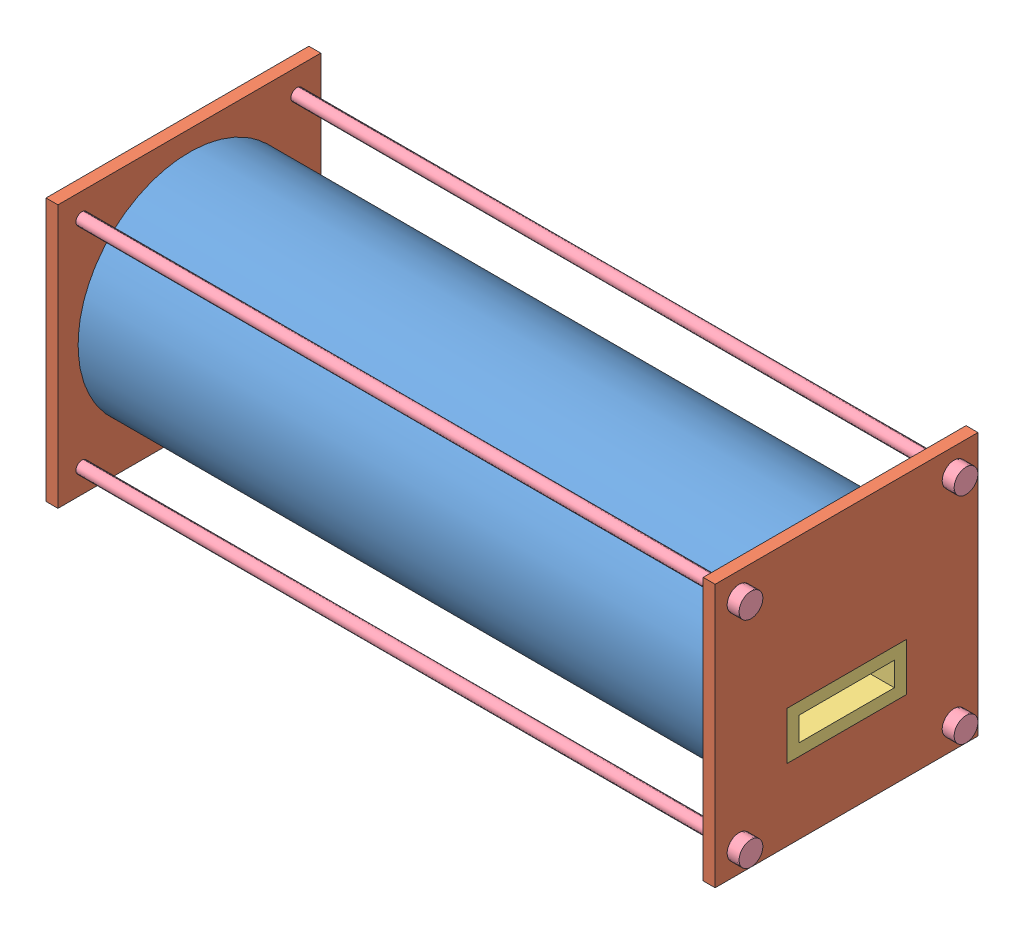
SolidWorks assembly Buoyancy_Cylinder_Assembly_1, configuration Default. Lengths in mm.
Overall size (580 220 220).
8 component instances, 4 part files, 17 mates.
Components (placement in the parent):
- Cylinder Body 1-1: Cylinder Body 1 [Default] at (-321.7289 98.8857 102.5905) size (550 186.35 186.35)
- End Caps 1-1: End Caps 1 [Default] at (233.2711 -11.1143 -7.4095) x (-1 0 0) z (0 0 -1) size (10 220 220)
- End Caps 1-2: End Caps 1 [Default] at (-326.7289 -11.1143 212.5905) size (10 220 220)
- Water Channel 1-1: Water Channel 1 [Default] at (-326.7289 48.8857 152.5905) size (560 40 100)
- End Cap Bolt 1-1: End Cap Bolt 1 [Default] at (-326.7289 8.8857 192.5905) size (580 20 20)
- End Cap Bolt 1-2: End Cap Bolt 1 [Default] at (-326.7289 188.8857 192.5905) size (580 20 20)
- End Cap Bolt 1-3: End Cap Bolt 1 [Default] at (-326.7289 8.8857 12.5905) size (580 20 20)
- End Cap Bolt 1-4: End Cap Bolt 1 [Default] at (-326.7289 188.8857 12.5905) size (580 20 20)
Mates (geometry in assembly coordinates):
- Coincident1: coincident anti-aligned: plane of Cylinder Body 1-1 through (-321.7289 98.8857 102.5905) normal (-1 0 0); plane of End Caps 1-2 through (-321.7289 98.8857 102.5905) normal (1 0 0)
- Concentric1: concentric anti-aligned: cylinder of Cylinder Body 1-1 through (228.2711 98.8857 102.5905) axis (-1 0 0) radius 93.1728; cylinder of End Caps 1-2 through (-321.7289 98.8857 102.5905) axis (1 0 0) radius 93.1728
- Coincident2: coincident anti-aligned: plane of Cylinder Body 1-1 through (228.2711 98.8857 102.5905) normal (1 0 0); plane of End Caps 1-1 through (228.2711 98.8857 102.5905) normal (-1 0 0)
- Concentric2: concentric aligned: cylinder of Cylinder Body 1-1 through (228.2711 98.8857 102.5905) axis (-1 0 0) radius 93.1728; cylinder of End Caps 1-1 through (228.2711 98.8857 102.5905) axis (-1 0 0) radius 93.1728
- Parallel1: parallel anti-aligned: line of End Caps 1-1 through (233.2711 -11.1143 -7.4095) axis (0 0 1); line of End Caps 1-2 through (-316.7289 -11.1143 212.5905) axis (0 0 -1)
- Coincident4: coincident aligned: plane of End Caps 1-1 through (233.2711 -11.1143 -7.4095) normal (1 0 0); plane of Water Channel 1-1 through (233.2711 48.8857 152.5905) normal (1 0 0)
- Coincident5: coincident anti-aligned: plane of End Caps 1-1 through (223.2711 88.8857 52.5905) normal (0 0 1); plane of Water Channel 1-1 through (233.2711 48.8857 52.5905) normal (0 0 -1)
- Coincident6: coincident anti-aligned: plane of End Caps 1-1 through (223.2711 48.8857 52.5905) normal (0 1 0); plane of Water Channel 1-1 through (233.2711 48.8857 152.5905) normal (0 -1 0)
- Parallel2: parallel: line of End Caps 1-1 through (233.2711 -11.1143 -7.4095) axis (0 0 1); plane of assembly
- Concentric3: concentric: cylinder of End Caps 1-2 through (-326.7289 188.8857 192.5905) axis (1 0 0) radius 5; cylinder of End Cap Bolt 1-2 through (233.2711 188.8857 192.5905) axis (-1 0 0) radius 5
- Coincident7: coincident anti-aligned: plane of End Caps 1-2 through (-326.7289 -11.1143 212.5905) normal (-1 0 0); plane of End Cap Bolt 1-2 through (-326.7289 188.8857 192.5905) normal (1 0 0)
- Concentric4: concentric: cylinder of End Caps 1-1 through (233.2711 188.8857 12.5905) axis (-1 0 0) radius 5; cylinder of End Cap Bolt 1-4 through (233.2711 188.8857 12.5905) axis (-1 0 0) radius 5
- Coincident8: coincident anti-aligned: plane of End Caps 1-1 through (233.2711 -11.1143 -7.4095) normal (1 0 0); plane of End Cap Bolt 1-4 through (233.2711 188.8857 12.5905) normal (-1 0 0)
- Concentric5: concentric: cylinder of End Caps 1-2 through (-326.7289 8.8857 192.5905) axis (1 0 0) radius 5; cylinder of End Cap Bolt 1-1 through (233.2711 8.8857 192.5905) axis (-1 0 0) radius 5
- Coincident9: coincident anti-aligned: plane of End Caps 1-2 through (-326.7289 -11.1143 212.5905) normal (-1 0 0); plane of End Cap Bolt 1-1 through (-326.7289 8.8857 192.5905) normal (1 0 0)
- Concentric6: concentric: cylinder of End Caps 1-2 through (-326.7289 8.8857 12.5905) axis (1 0 0) radius 5; cylinder of End Cap Bolt 1-3 through (233.2711 8.8857 12.5905) axis (-1 0 0) radius 5
- Coincident10: coincident anti-aligned: plane of End Caps 1-2 through (-326.7289 -11.1143 212.5905) normal (-1 0 0); plane of End Cap Bolt 1-3 through (-326.7289 8.8857 12.5905) normal (1 0 0)
